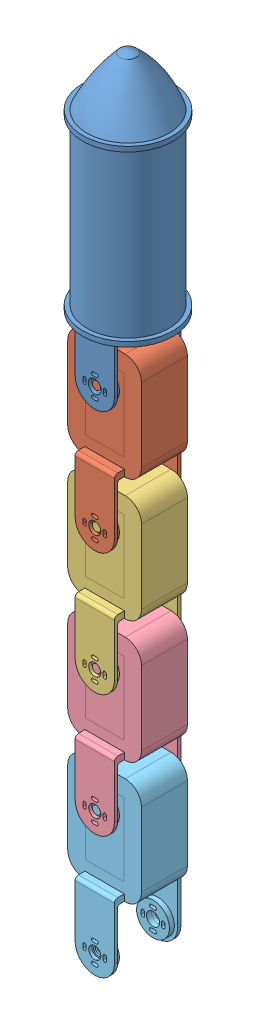
SolidWorks assembly test4, configuration 預設. Lengths in mm.
Overall size (55 478.78 55).
5 component instances, 5 part files, 19 mates.
Components (placement in the parent):
- base_link2-2: base_link2 [預設] at origin size (55 179.98 55)
- link1-1: link1 [預設] at (0 -157.7 0) x (0 1 0) z (0 0 -1) size (107 45 40.5)
- link2-1: link2 [預設] at (0 -232.4 0) x (0 1 0) z (0 0 -1) size (107 45 40.5)
- link3-2: link3 [預設] at (0 -307.1 0) x (0 1 0) z (0 0 -1) size (107 45 40.5)
- link4-1: link4 [預設] at (0 -381.8 0) x (0 1 0) z (0 0 -1) size (107 45 40.5)
Mates (geometry in assembly coordinates):
- 平行相距4: distance = 18.5 mm: plane of base_link2-2 through (0 -83 -18.5) normal (0 0 1); plane of assembly through (0 0 0) normal (0 0 1)
- 平行相距5: distance = 12 mm: plane of assembly through (0 0 0) normal (1 0 0); plane of base_link2-2 through (12 -53 18) normal (1 0 0)
- 平行相距6: distance = 50 mm: plane of assembly through (0 0 0) normal (0 1 0); plane of base_link2-2 through (0 -50 -0.25) normal (0 1 0)
- 同軸心2: concentric: cylinder of base_link2-2 through (0 -83 18) axis (0 0 1) radius 4; cylinder of link1-1 through (0 -83 14) axis (0 0 1) radius 2.5
- 同軸心3: concentric: cylinder of base_link2-2 through (0 -83 -20.5) axis (0 0 1) radius 4; cylinder of link1-1 through (0 -83 -19) axis (0 0 1) radius 2.5
- 平行1: parallel: plane of base_link2-2 through (12 -53 -20.5) normal (1 0 0); plane of link1-1 through (22.5 -127.7 -14) normal (1 0 0)
- 重合/共線/共點8: coincident: plane of base_link2-2 through (0 -83 -18.5) normal (0 0 1); plane of link1-1 through (0 -157.7 -18.5) normal (0 0 1)
- 同軸心4: concentric: cylinder of link1-1 through (0 -157.7 20) axis (0 0 -1) radius 3.7; cylinder of ? through (122.3295 -185.6512 7.75) axis (0 0 -1) radius 2.5
- 重合/共線/共點9: coincident: plane of link1-1 through (22.5 -127.7 -14) normal (1 0 0); plane of ?
- 重合/共線/共點10: coincident: plane of link1-1 through (0 -67.7653 20) normal (0 0 1); plane of ?
- 重合/共線/共點11: coincident: plane of link1-1 through (22.5 -127.7 -14) normal (1 0 0); plane of link2-1 through (22.5 -202.4 -14) normal (1 0 0)
- 同軸心5: concentric: cylinder of link1-1 through (0 -157.7 20) axis (0 0 -1) radius 3.7; cylinder of link2-1 through (0 -157.7 14) axis (0 0 1) radius 2.5
- 重合/共線/共點12: coincident: plane of link1-1 through (0 -67.7653 14) normal (0 0 1); plane of link2-1 through (0 -142.4653 14) normal (0 0 1)
- 重合/共線/共點14: coincident: plane of link2-1 through (22.5 -202.4 -14) normal (1 0 0); plane of link3-2 through (22.5 -277.1 -14) normal (1 0 0)
- 同軸心6: concentric: cylinder of link2-1 through (0 -232.4 -18.5) axis (0 0 -1) radius 4; cylinder of link3-2 through (0 -232.4 -19) axis (0 0 1) radius 2.5
- 重合/共線/共點15: coincident: plane of link2-1 through (0 -142.4653 -14) normal (0 0 -1); plane of link3-2 through (0 -217.1653 -14) normal (0 0 -1)
- 同軸心7: concentric: cylinder of link3-2 through (0 -307.1 20) axis (0 0 -1) radius 3.7; cylinder of link4-1 through (0 -307.1 14) axis (0 0 1) radius 2.5
- 重合/共線/共點16: coincident: plane of link3-2 through (22.5 -277.1 -14) normal (1 0 0); plane of link4-1 through (22.5 -351.8 -14) normal (1 0 0)
- 重合/共線/共點17: coincident: plane of link3-2 through (0 -217.1653 14) normal (0 0 1); plane of link4-1 through (0 -291.8653 14) normal (0 0 1)
